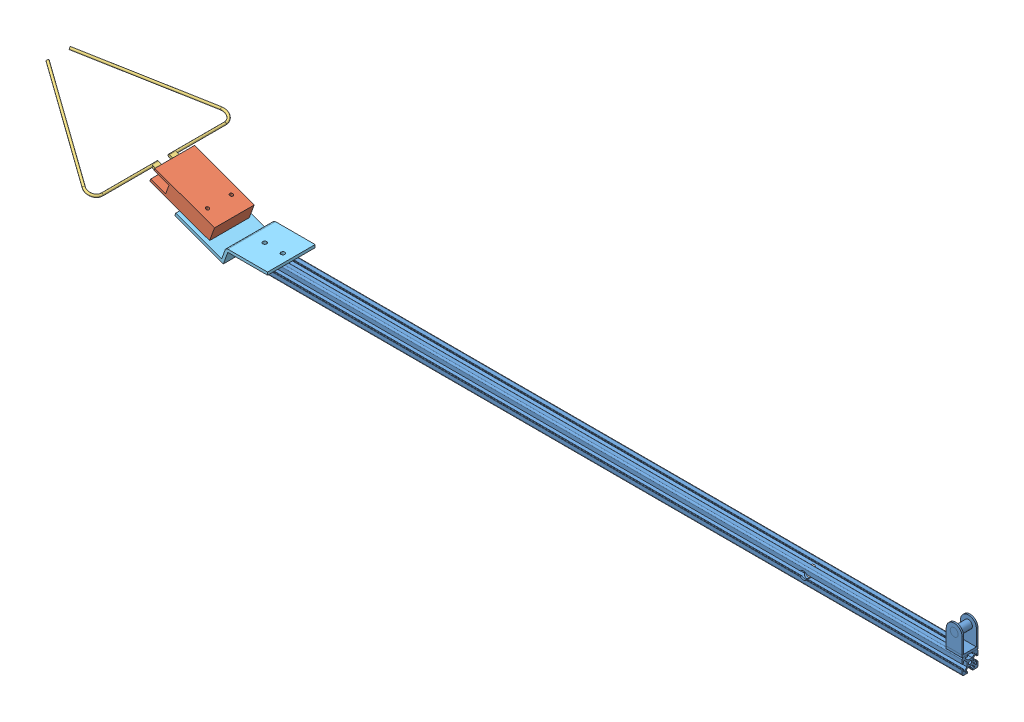
SolidWorks assembly gripper 22, configuration Default. Lengths in mm.
Overall size (1149.08 112.67 178.37).
7 component instances, 5 part files, 7 mates.
Components (placement in the parent):
- arm-1: arm [Default<As Machined>] at (854.8312 426.86 748.0498) size (900 53 20)
- gripper 1-1: gripper 1 [Default] at (-244.0948 417.4832 681.2305) x (0.939693 -0.34202 0) z (0 0 1) size (231.33 18 178.37) (flexible)
  - gripper base-1: gripper base [Default] at (16.831 37.4029 66.8193) size (80 18 55)
  - finger-1: finger [Default] at (-17.169 40.4029 73.8193) x (0 0 -1) z (1 0 0) size (92.18 3 165.33)
  - finger-2: finger [Default] at (-17.169 43.4029 59.8193) x (0 0 1) z (1 0 0) size (92.18 3 165.33)
  - gripper rod-1: gripper rod [Default] at (-6.169 48.4029 66.8193) x (0 0 1) z (1 0 0) size (6 11 22)
- clamp-1: clamp [Default] at (-155.6033 421.3536 778.0498) x (-0.939693 0.34202 0) z (0 0 -1) size (111.98 36.89 60)
Mates (geometry in assembly coordinates):
- Coincident2: coincident anti-aligned: plane of arm-1 through (-145.1688 436.8585 756.0498) normal (0 1 0); plane of clamp-1 through (-149.96 436.8585 778.0498) normal (0 -1 0)
- Width1: width anti-aligned: plane of arm-1 through (-145.1688 434.8585 758.0498) normal (0 0 1); plane of arm-1 through (-145.1688 434.8585 738.0498) normal (0 0 -1); plane of clamp-1 through (-154.4063 424.6425 718.0498) normal (0 0 -1); plane of clamp-1 through (-154.4063 424.6425 778.0498) normal (0 0 1)
- Concentric1: concentric aligned: cylinder of arm-1 through (-133.7641 405.2839 747.8686) axis (0 1 0) radius 2.5; cylinder of clamp-1 through (-133.7641 380.3585 747.8686) axis (0 1 0) radius 2.5
- Concentric2: concentric aligned: cylinder of arm-1 through (-110.7641 405.2839 747.8686) axis (0 1 0) radius 2.5; cylinder of clamp-1 through (-110.7641 380.3585 747.8686) axis (0 1 0) radius 2.5
- Concentric3: concentric aligned: cylinder of gripper-1/gripper base-1 through (-207.295 410.903 763.0498) axis (0.34202 0.939693 0) radius 2; cylinder of clamp-1 through (-217.2136 383.6519 763.0498) axis (0.34202 0.939693 0) radius 2
- Concentric4: concentric aligned: cylinder of gripper-1/gripper base-1 through (-207.295 410.903 733.0498) axis (0.34202 0.939693 0) radius 2; cylinder of clamp-1 through (-217.2136 383.6519 733.0498) axis (0.34202 0.939693 0) radius 2
- Coincident3: coincident anti-aligned: plane of gripper-1/gripper base-1 through (-215.4863 446.8738 748.0498) normal (-0.34202 -0.939693 0); plane of clamp-1 through (-154.4063 424.6425 778.0498) normal (0.34202 0.939693 0)
